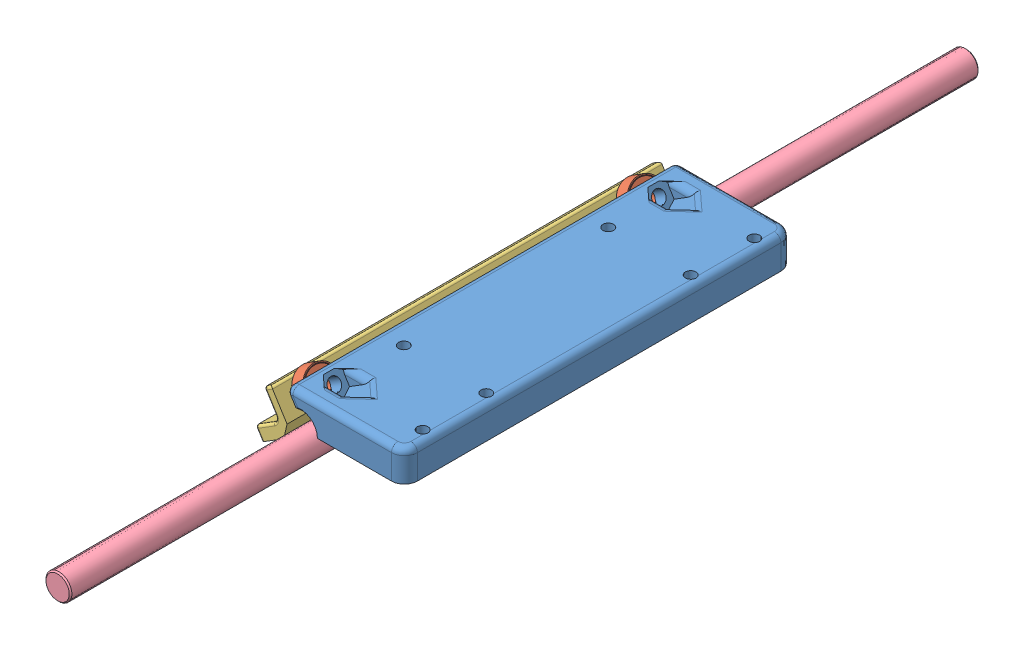
SolidWorks assembly sE1X OpenY carriage ass, configuration Default. Lengths in mm.
Overall size (63.17 29.21 350).
7 component instances, 4 part files, 15 mates.
Components (placement in the parent):
- sE1X OpenY carriage-1: sE1X OpenY carriage [Default] at (-16.8932 -31.1143 22.0387) size (45.49 12.38 151.23)
- 605Z Ball bearing-1: 605Z Ball bearing [Default] at (-24.8832 -27.7643 -40.4613) x (0.529999 -0.847998 0) z (0 0 1) size (14 5 14)
- 605Z Ball bearing-2: 605Z Ball bearing [Default] at (-24.8832 -27.7643 84.5387) x (0.529999 -0.847998 0) z (0 0 1) size (14 5 14)
- sE1X OpenY carriage side bracket(x2)-1: sE1X OpenY carriage side bracket(x2) [Default] at (-26.7117 -38.0463 22.0387) x (-0.847998 -0.529999 0) z (0 0 -1) size (14 15.5 150)
- 605Z Ball bearing-3: 605Z Ball bearing [Default] at (-24.9627 -44.6183 -30.4627) x (0.847998 0.529999 0) z (0 0 1) size (14 5 14)
- 605Z Ball bearing-4: 605Z Ball bearing [Default] at (-24.9627 -44.6183 74.5401) x (0.847998 0.529999 0) z (0 0 1) size (14 5 14)
- Z Axis 10mm smooth rod-1: Z Axis 10mm smooth rod [Default] at (-15.9792 -36.3503 -158.4721) x (0.802808 0.596238 0) z (0 0 1) size (10 10 350)
Mates (geometry in assembly coordinates):
- Concentric1: concentric anti-aligned: circle of sE1X OpenY carriage-1; circle of 605Z Ball bearing-1
- Coincident1: coincident anti-aligned: plane of sE1X OpenY carriage-1 through (-16.8932 -31.1143 97.0388) normal (-0.847998 -0.529999 0); plane of 605Z Ball bearing-1 through (-20.6432 -25.1143 -40.4613) normal (0.847998 0.529999 0)
- Concentric2: concentric anti-aligned: circle of sE1X OpenY carriage-1; circle of 605Z Ball bearing-2
- Coincident2: coincident anti-aligned: plane of sE1X OpenY carriage-1 through (-16.8932 -31.1143 97.0388) normal (-0.847998 -0.529999 0); plane of 605Z Ball bearing-2 through (-20.6432 -25.1143 84.5387) normal (0.847998 0.529999 0)
- Coincident22: coincident anti-aligned: plane of 605Z Ball bearing-1 through (-24.8832 -27.7643 -40.4613) normal (-0.847998 -0.529999 0); plane of sE1X OpenY carriage side bracket(x2)-1 through (-19.9807 -35.6083 -52.9613) normal (0.847998 0.529999 0)
- Coincident23: coincident anti-aligned: circle of 605Z Ball bearing-2; circle of sE1X OpenY carriage side bracket(x2)-1
- Coincident24: coincident anti-aligned: circle of 605Z Ball bearing-1; circle of sE1X OpenY carriage side bracket(x2)-1
- Coincident25: coincident aligned: circle of sE1X OpenY carriage side bracket(x2)-1; plane of 605Z Ball bearing-3 through (-27.6127 -40.3783 -30.4627) normal (-0.529999 0.847998 0)
- Concentric9: concentric aligned: circle of sE1X OpenY carriage side bracket(x2)-1; circle of 605Z Ball bearing-4
- Coincident27: coincident anti-aligned: plane of sE1X OpenY carriage side bracket(x2)-1 through (-25.9167 -39.3183 22.0387) normal (0.529999 -0.847998 0); circle of 605Z Ball bearing-4
- Tangent12: tangent anti-aligned: cylinder of 605Z Ball bearing-4 through (-27.6127 -40.3783 74.5401) axis (0.529999 -0.847998 0) radius 7; cylinder of Z Axis 10mm smooth rod-1 through (-15.9792 -36.3503 191.5279) axis (0 0 -1) radius 5
- Tangent13: tangent anti-aligned: cylinder of 605Z Ball bearing-1 through (-20.6432 -25.1143 -40.4613) axis (-0.847998 -0.529999 0) radius 7; cylinder of Z Axis 10mm smooth rod-1 through (-15.9792 -36.3503 191.5279) axis (0 0 -1) radius 5
- Tangent14: tangent anti-aligned: cylinder of 605Z Ball bearing-3 through (-27.6127 -40.3783 -30.4627) axis (0.529999 -0.847998 0) radius 7; cylinder of Z Axis 10mm smooth rod-1 through (-15.9792 -36.3503 191.5279) axis (0 0 -1) radius 5
- Concentric22: concentric aligned: circle of sE1X OpenY carriage side bracket(x2)-1; circle of 605Z Ball bearing-3
- Concentric24: concentric aligned: cylinder of sE1X OpenY carriage side bracket(x2)-1 through (-27.6127 -40.3783 74.5401) axis (-0.529999 0.847998 0) radius 2.625; circle of 605Z Ball bearing-4
